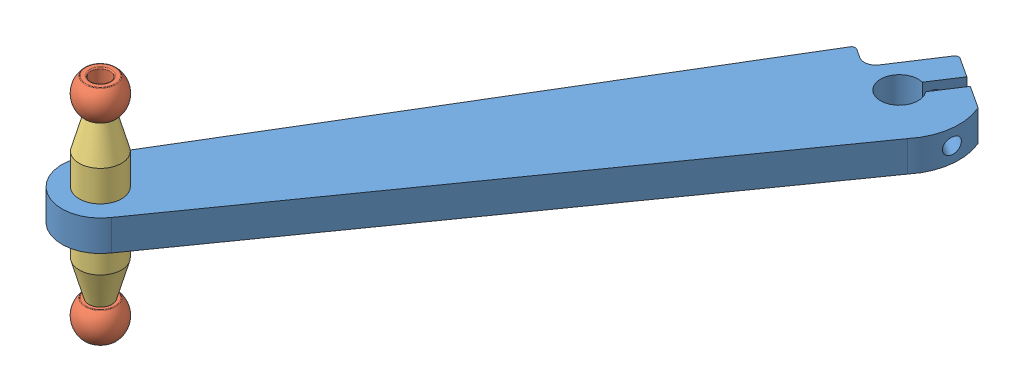
SolidWorks assembly MixLongTruNhua, configuration Default. Lengths in mm.
Overall size (120.45 58 161.7).
6 component instances, 3 part files, 8 mates.
Components (placement in the parent):
- CanhTayTren-1: CanhTayTren [Default] at (42.6073 26.3646 -53.4371) x (-0.837169 0 -0.546944) z (0 1 0) size (30.85 173 8)
- Ball Joint 5x008-1: Ball Joint 5x008 [M22*1.5] at (0.7661 5.3646 10.6063) size (11.11 8 11.11)
- Long Tru Nhua-1: Long Tru Nhua [Default] at (0.7661 26.3646 10.6063) x (-0.515153 0 -0.857098) z (-0.857098 0 0.515153) size (11 17 11)
- Long Tru Nhua-2: Long Tru Nhua [Default] at (0.7661 34.3646 10.6063) x (0.837169 0 -0.546944) z (0.546944 0 0.837169) size (11 17 11)
- Ball Joint 5x008-2: Ball Joint 5x008 [M22*1.5] at (0.7661 55.3646 10.6063) x (-1 0 0) z (0 0 1) size (11.11 8 11.11)
- Assem2^MixLongTruNhua-1: Assem2^MixLongTruNhua [Default] at origin (virtual)
Mates (geometry in assembly coordinates):
- Concentric2: concentric anti-aligned: circle of Ball Joint 5x008-1; circle of Long Tru Nhua-1
- Coincident2: coincident anti-aligned: plane of Ball Joint 5x008-1 through (4.6207 9.3646 10.6063) normal (0 1 0); plane of Long Tru Nhua-1 through (-0.7794 9.3646 8.035) normal (0 -1 0)
- Concentric3: concentric anti-aligned: circle of Long Tru Nhua-2; circle of Ball Joint 5x008-2
- Coincident3: coincident anti-aligned: plane of Long Tru Nhua-2 through (3.2776 51.3646 8.9655) normal (0 1 0); plane of Ball Joint 5x008-2 through (-3.0885 51.3646 10.6063) normal (0 -1 0)
- Concentric4: concentric aligned: circle of Long Tru Nhua-1; circle of CanhTayTren-1
- Coincident4: coincident anti-aligned: plane of Long Tru Nhua-1 through (-1.8097 26.3646 6.3208) normal (0 1 0); plane of CanhTayTren-1 through (42.6073 26.3646 -53.4371) normal (0 -1 0)
- Concentric5: concentric anti-aligned: circle of Long Tru Nhua-2; circle of CanhTayTren-1
- Coincident5: coincident anti-aligned: plane of Long Tru Nhua-2 through (4.9519 34.3646 7.8716) normal (0 -1 0); plane of CanhTayTren-1 through (42.6073 34.3646 -53.4371) normal (0 1 0)
